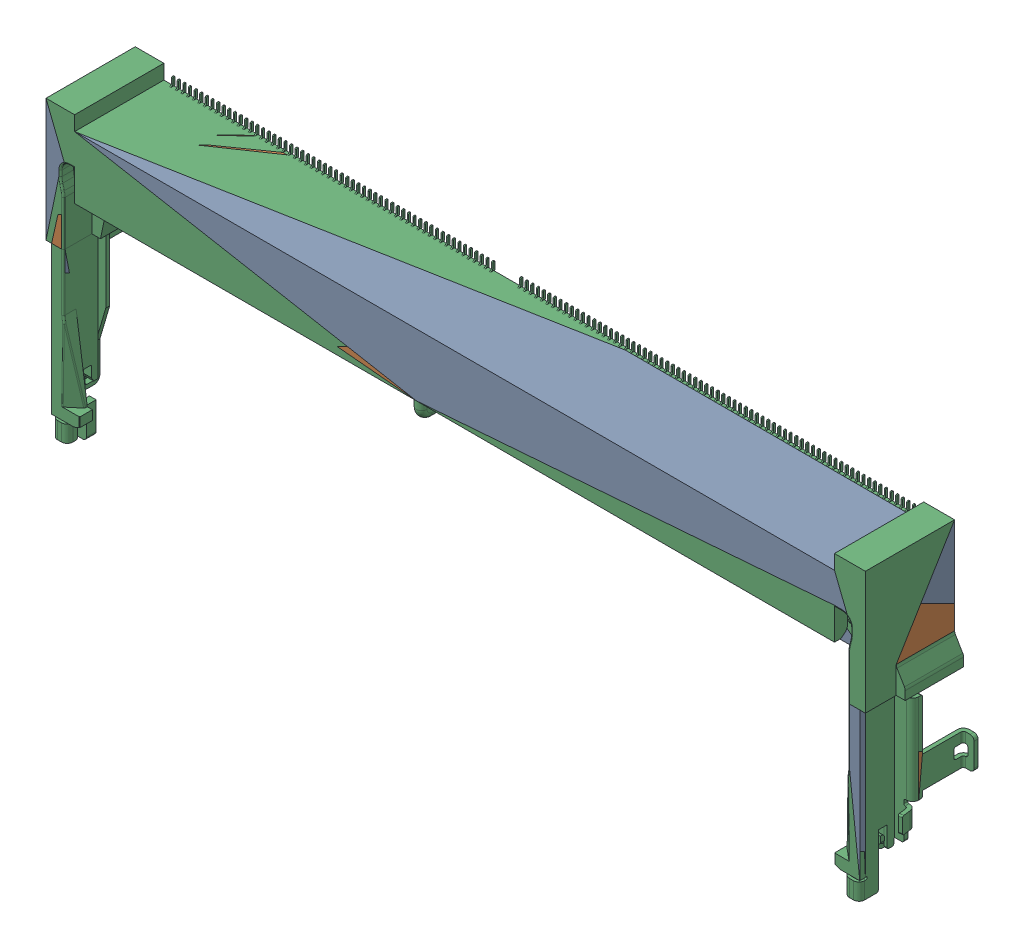
SolidWorks assembly P1, configuration Défaut. Lengths in mm.
Overall size (77.02 25.85 8.49).
3 component instances, 2 part files, 0 mates.
Components (placement in the parent):
- ASAA826-E8SB0-7H-1: ASAA826-E8SB0-7H [Défaut] at (33.1634 4.5414 -1.5) x (1 0 0) z (0 0 1) size (77.02 25.85 8.49)
- ASAA826-E8SB0-7H-2: ASAA826-E8SB0-7H [Défaut] at (33.1634 4.5414 -1.5) x (1 0 0) z (0 0 1) size (77.02 25.85 8.49)
- ASAA826-E8SB0-7H_1755-1: ASAA826-E8SB0-7H_1755 [Défaut] at (33.1634 4.5414 -1.5) x (1 0 0) z (0 0 1) size (77.02 25.85 8.49)
